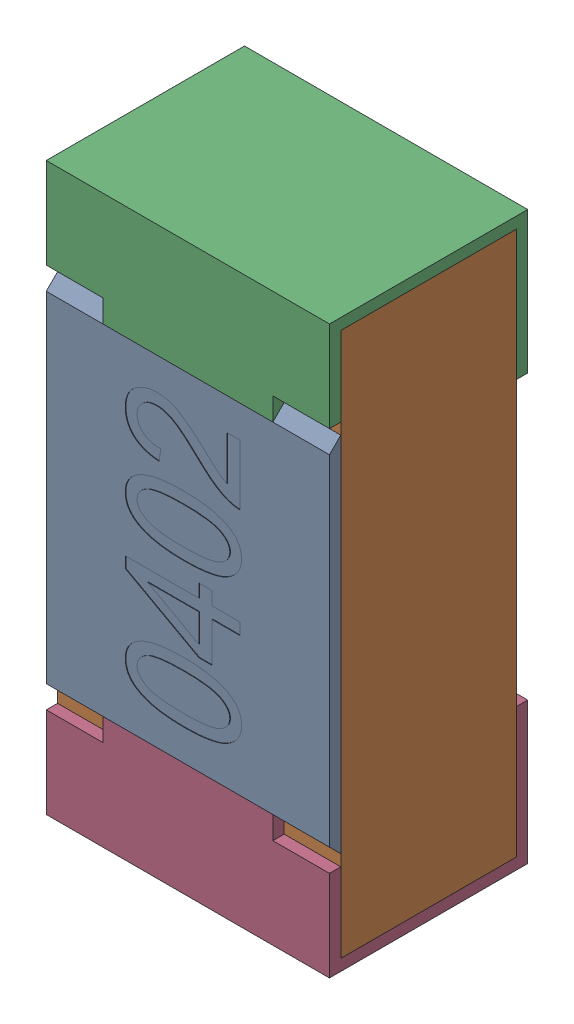
SolidWorks assembly R21, configuration Standard. Lengths in mm.
Overall size (0.5 1 0.35).
5 component instances, 4 part files, 0 mates.
Components (placement in the parent):
- R21-subassembly-1-1: R21-subassembly-1 [Standard] at (-11.8 -9.4999 0) x (0 1 0) z (0 0 1) size (1 0.5 0.35)
  - User Library-R_0402-1: User Library-R_0402 [Standard] at origin size (0.64 0.5 0.02)
  - User Library-R_0402-1-1: User Library-R_0402-1 [Standard] at origin size (0.96 0.5 0.31)
  - User Library-R_0402-2-1: User Library-R_0402-2 [Standard] at origin size (0.25 0.5 0.35)
  - User Library-R_0402-3-1: User Library-R_0402-3 [Standard] at origin size (0.25 0.5 0.35)
